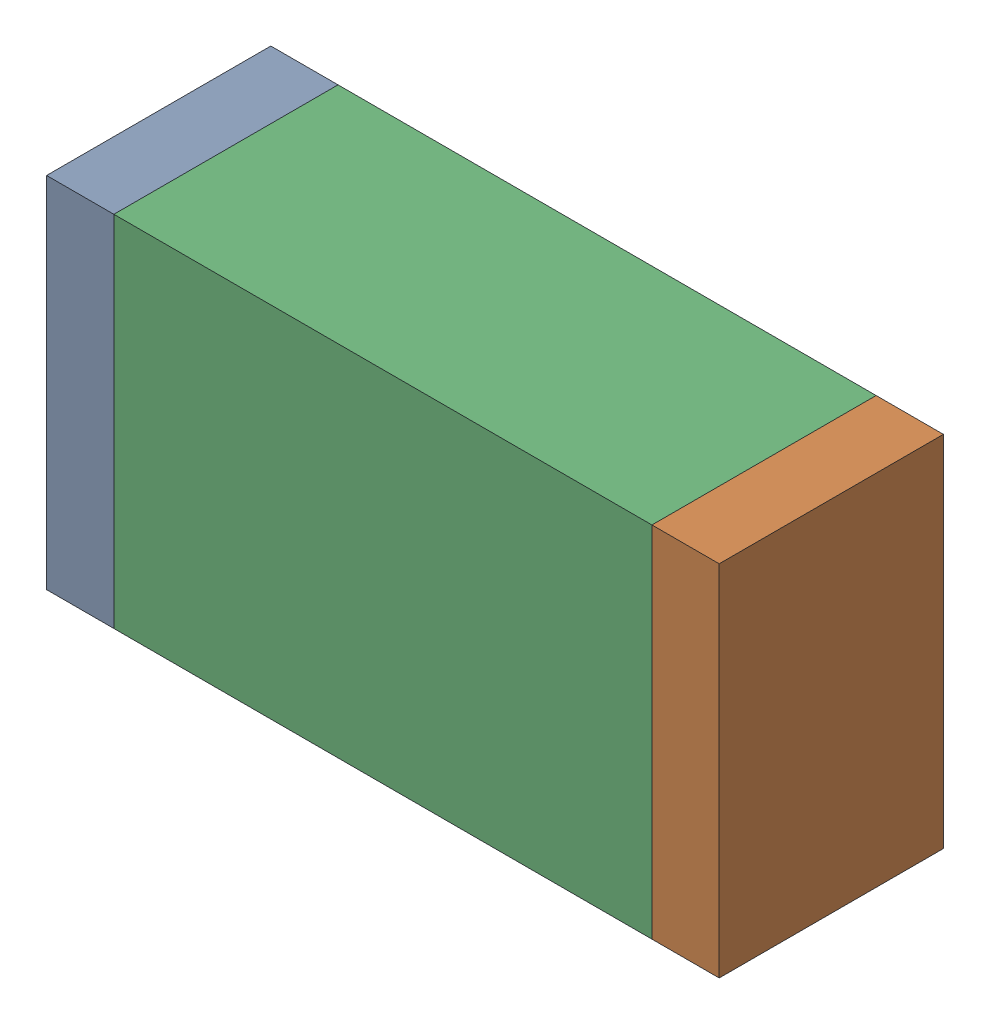
SolidWorks assembly R51, configuration Default. Lengths in mm.
Overall size (1.5 0.8 0.5).
6 component instances, 2 part files, 0 mates.
Components (placement in the parent):
- 836752496-1: 836752496 [Default] at (126.875 60.75 0) size (0.15 0.8 0.5)
  - Extruded_2-1: Extruded_2 [Default] at origin size (0.15 0.8 0.5)
- 836752496-2: 836752496 [Default] at (128.225 60.75 0) size (0.15 0.8 0.5)
  - Extruded_2-1: Extruded_2 [Default] at origin size (0.15 0.8 0.5)
- 836752368-1: 836752368 [Default] at (127.55 60.75 0) size (1.2 0.8 0.5)
  - Extruded-1: Extruded [Default] at origin size (1.2 0.8 0.5)
